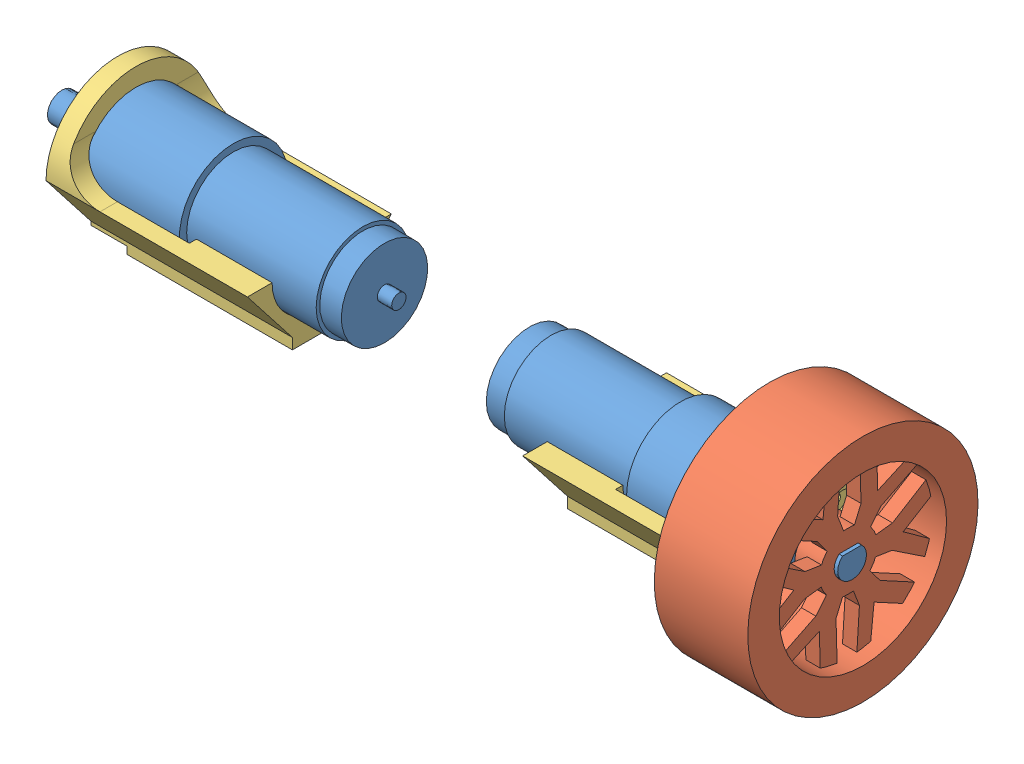
SolidWorks assembly SmallRobotMotorBlock-2, configuration Default. Lengths in mm.
Overall size (222.7 65.17 65.17).
5 component instances, 3 part files, 11 mates.
Components (placement in the parent):
- 2642W_CR_with_30-1S_Ratio3_71-1: 2642W_CR_with_30-1S_Ratio3_71 [Défaut] at (-1.5329 58.3002 84.8) size (93.7 30 30)
- Wheel-Traction-63x26mm-1: Wheel-Traction-63x26mm [Défaut] at (69.1671 58.3002 84.8) x (0 -0.01847 -0.999829) z (1 0 0) size (64 64 26)
- SmallRobotMotorSupportForPlate-1: SmallRobotMotorSupportForPlate [Default] at (20.5671 58.3002 84.8) x (0 0 -1) z (1 0 0) size (40 39 56)
- 2642W_CR_with_30-1S_Ratio3_71-2: 2642W_CR_with_30-1S_Ratio3_71 [Défaut] at (-33.8329 58.3002 84.8) x (-1 0 0) z (0 -1 0) size (93.7 30 30)
- SmallRobotMotorSupportForPlate-2: SmallRobotMotorSupportForPlate [Default] at (-55.9329 58.3002 84.8) x (0 0 1) z (-1 0 0) size (40 39 56)
Mates (geometry in assembly coordinates):
- Concentric1: concentric anti-aligned: circle of 2642W_CR_with_30-1S_Ratio3_71-1; circle of Wheel-Traction-63x26mm-1
- Concentric2: concentric aligned: cylinder of 2642W_CR_with_30-1S_Ratio3_71-1 through (-1.5329 58.3002 84.8) axis (-1 0 0) radius 9; cylinder of SmallRobotMotorSupportForPlate-1 through (76.5671 58.3002 84.8) axis (-1 0 0) radius 9.1
- Concentric3: concentric aligned: cylinder of 2642W_CR_with_30-1S_Ratio3_71-1 through (68.5671 71.3002 84.8) axis (1 0 0) radius 1.5; cylinder of SmallRobotMotorSupportForPlate-1 through (74.5671 71.3002 84.8) axis (1 0 0) radius 3.25
- Coincident3: coincident anti-aligned: plane of 2642W_CR_with_30-1S_Ratio3_71-1 through (71.5671 67.3002 84.8) normal (1 0 0); plane of SmallRobotMotorSupportForPlate-1 through (71.5671 58.3002 84.8) normal (-1 0 0)
- Concentric4: concentric anti-aligned: cylinder of 2642W_CR_with_30-1S_Ratio3_71-1 through (-1.5329 58.3002 84.8) axis (-1 0 0) radius 2; cylinder of 2642W_CR_with_30-1S_Ratio3_71-2 through (-33.8329 58.3002 84.8) axis (1 0 0) radius 2
- Coincident4: coincident anti-aligned: plane of 2642W_CR_with_30-1S_Ratio3_71-2 through (-106.9329 58.3002 75.8) normal (-1 0 0); plane of SmallRobotMotorSupportForPlate-2 through (-106.9329 58.3002 84.8) normal (1 0 0)
- Concentric5: concentric aligned: cylinder of 2642W_CR_with_30-1S_Ratio3_71-2 through (-33.8329 58.3002 84.8) axis (1 0 0) radius 9; cylinder of SmallRobotMotorSupportForPlate-2 through (-111.9329 58.3002 84.8) axis (1 0 0) radius 9.1
- Concentric6: concentric aligned: circle of 2642W_CR_with_30-1S_Ratio3_71-2; circle of SmallRobotMotorSupportForPlate-2
- Coincident6: coincident aligned: plane of SmallRobotMotorSupportForPlate-1 through (76.5671 39.3002 92.3) normal (0 -1 0); plane of SmallRobotMotorSupportForPlate-2 through (-111.9329 39.3002 77.3) normal (0 -1 0)
- Distance2: distance = 76.5 mm anti-aligned: plane of SmallRobotMotorSupportForPlate-2 through (-55.9329 58.3002 84.8) normal (1 0 0); plane of SmallRobotMotorSupportForPlate-1 through (20.5671 58.3002 84.8) normal (-1 0 0)
- Distance3: distance = 3 mm aligned: plane of 2642W_CR_with_30-1S_Ratio3_71-1 through (92.1671 58.3002 84.8) normal (1 0 0); plane of Wheel-Traction-63x26mm-1 through (95.1671 58.3002 84.8) normal (1 0 0)
